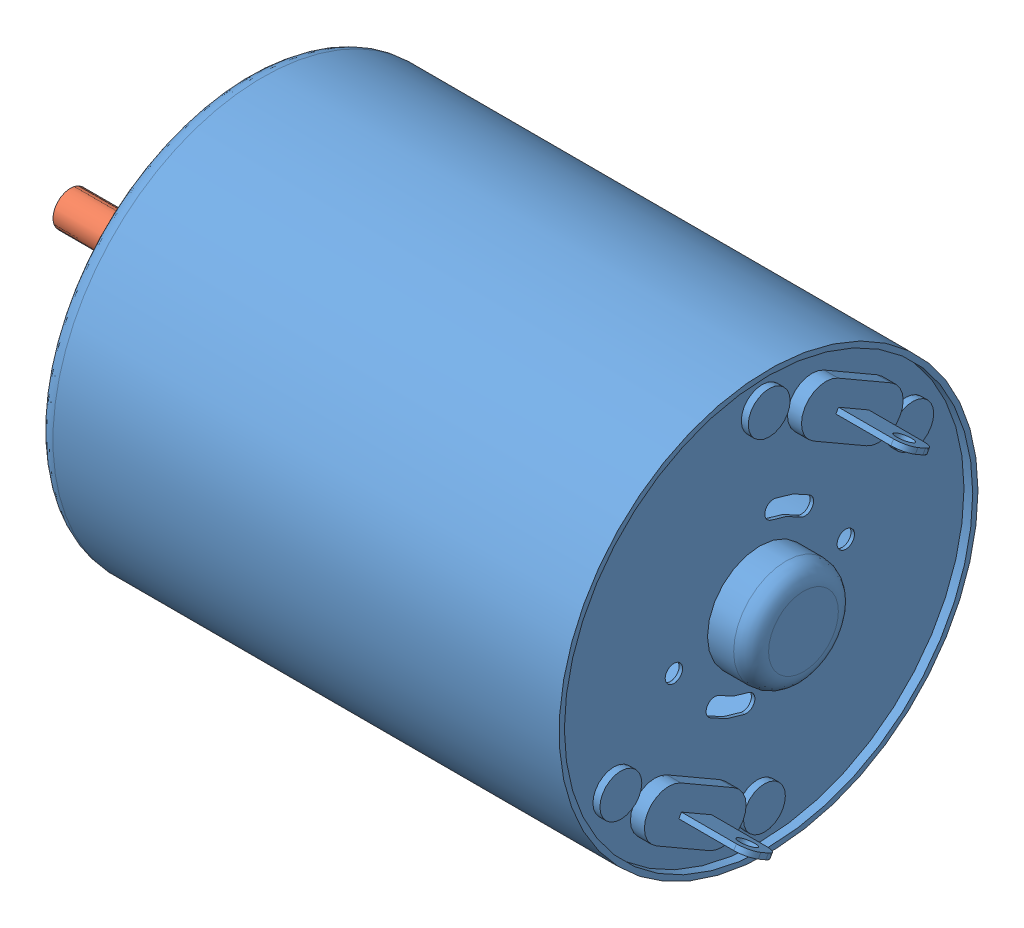
SolidWorks assembly DC Motor, Chihai CHW-GW4632-370, DC Worm Gear Motor, 6 V, 6 RPM, configuration Default. Lengths in mm.
2 component instances, 2 part files, 3 mates.
Components (placement in the parent):
- DC Motor Body, Chihai CHW-GW4632-370, DC Worm Gear Motor, 6 V, 6 RPM-1: DC Motor Body, Chihai CHW-GW4632-370, DC Worm Gear Motor, 6 V, 6 RPM [Default] at origin size (34.2 24 24)
- DC Motor Shaft, Chihai CHW-GW4632-370, DC Worm Gear Motor, 6 V, 6 RPM-1: DC Motor Shaft, Chihai CHW-GW4632-370, DC Worm Gear Motor, 6 V, 6 RPM [Default] at (-20 0 0) x (1 0 0) z (0 0.450234 0.89291) size (40 2 2)
Mates (geometry in assembly coordinates):
- Coincident1: coordinate: point of DC Motor Body, Chihai CHW-GW4632-370, DC Worm Gear Motor, 6 V, 6 RPM-1
- Concentric1: concentric aligned: cylinder of DC Motor Body, Chihai CHW-GW4632-370, DC Worm Gear Motor, 6 V, 6 RPM-1 through (4.201 0 0) axis (-1 0 0) radius 1; cylinder of DC Motor Shaft, Chihai CHW-GW4632-370, DC Worm Gear Motor, 6 V, 6 RPM-1 through (0 0 0) axis (-1 0 0) radius 1
- Distance1: distance = 10 mm aligned: plane of DC Motor Body, Chihai CHW-GW4632-370, DC Worm Gear Motor, 6 V, 6 RPM-1 through (-30 0 0) normal (-1 0 0); plane of DC Motor Shaft, Chihai CHW-GW4632-370, DC Worm Gear Motor, 6 V, 6 RPM-1 through (-40 0 0) normal (-1 0 0)
